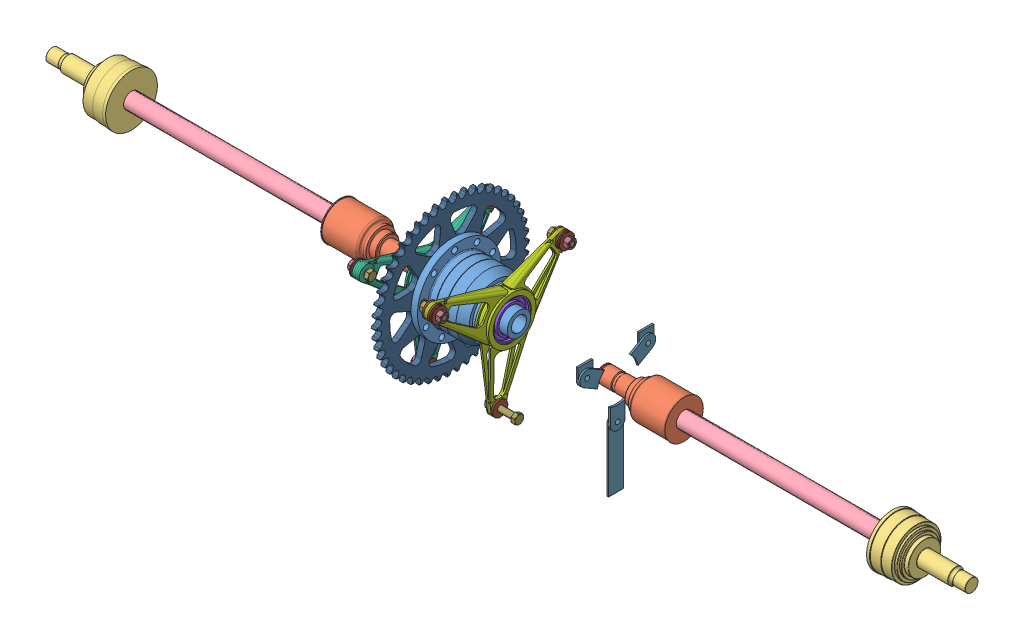
SolidWorks assembly AxleRear, configuration Simplified. Lengths in mm.
Overall size (1562.27 332.85 319.63).
54 component instances, 14 part files, 101 mates.
Components (placement in the parent):
- DifferentialHonda-1: DifferentialHonda [Default] at (-112.1 0 0) x (1 0 0) z (0 -0.982925 0.184005)
- HalfshaftCivicLeft-1: HalfshaftCivicLeft [Default] at (-315.2356 0 0) x (1 0 0) z (0 -0.94625 -0.323438) size (624.85 124.16 124.16) (flexible)
  - CVjointCivicInner-1: CVjointCivicInner [Default] at origin size (136.25 65.07 65.07)
  - CVjointCivicOuter-1: CVjointCivicOuter [Default] at (-354 0 0) x (-1 0 0) z (0 -0.656823 -0.754045) size (134.6 88 88)
  - AxleLeftRear-1: AxleLeftRear [Default] at (-177 0 0) x (1 0 0) z (0 -0.10869 0.994076) size (354 27 27)
- HalfshaftCivicLeft-3: HalfshaftCivicLeft [Default] at (269.8356 0 0) x (-1 0 0) z (0 -0.942827 -0.333282) size (624.85 124.16 124.16)
  - CVjointCivicInner-1: CVjointCivicInner [Default] at origin size (136.25 65.07 65.07)
  - CVjointCivicOuter-1: CVjointCivicOuter [Default] at (-354 0 0) x (-1 0 0) z (0 -0.656823 -0.754045) size (134.6 88 88)
  - AxleLeftRear-1: AxleLeftRear [Default] at (-177 0 0) x (1 0 0) z (0 -0.10869 0.994076) size (354 27 27)
- Basic Internal Retaining Ring_am-1: Basic Internal Retaining Ring_am [B27.7M - 3BM1-70] at (-39 0 0) x (0 0.02748 -0.999622) z (1 0 0)
- Basic Internal Retaining Ring_am-2: Basic Internal Retaining Ring_am [B27.7M - 3BM1-70] at (-144.05 0 0) x (0 0.383049 0.923728) z (1 0 0)
- DifferentialSupportLeft5-1: DifferentialSupportLeft5 [Finished Part] at (-127.45 0 0) x (0 0 1) z (-1 0 0)
- DifferentialSupportRight3-1: DifferentialSupportRight3 [Finished Part] at (-22.25 0 0) x (0 0 1) z (-1 0 0)
- Radial Ball Bearing_68_SKF-1: Radial Ball Bearing_68_SKF [SKF - 6008 - 16,SI,NC,16_68] at (-31.5 0 0)
- Radial Ball Bearing_68_SKF-2: Radial Ball Bearing_68_SKF [SKF - 6008 - 16,SI,NC,16_68] at (-136.55 0 0) x (-1 0 0) z (0 -0.924225 -0.381849)
- Hex Flange Machine Screw_AM-2: Hex Flange Machine Screw_AM [B18.6.7M - M10 x 1.5 x 20 Indented HFMS --20N] at (-143.1226 11.5003 61.4328)
- Sprocket50Real-1: Sprocket50Real [Default] at (-127.7363 0 0) x (0 0.982925 -0.184005) z (1 0 0)
- Flat Washer Type B Regular_AI-1: Flat Washer Type B Regular_AI [Regular FW 0.375] at (-168.05 62.2 116.6) x (1 0 0) z (0 -0.091606 0.995795)
- Hex Bolt_AI-1: Hex Bolt_AI [HBOLT 0.3750-24x1.125x1-N] at (-143.2428 62.2 116.6) x (-1 0 0) z (0 0.99306 0.117612)
- Flat Washer Type B Regular_AI-2: Flat Washer Type B Regular_AI [Regular FW 0.375] at (-162.05 62.4 -100.2)
- Flat Washer Type B Regular_AI-3: Flat Washer Type B Regular_AI [Regular FW 0.375] at (-163.6502 62.4 -100.2)
- Flat Washer Type B Regular_AI-4: Flat Washer Type B Regular_AI [Regular FW 0.375] at (-156.05 62.4 -100.2) x (-1 0 0) z (0 0.924225 0.381849)
- Flat Washer Type B Regular_AI-5: Flat Washer Type B Regular_AI [Regular FW 0.375] at (-154.4498 62.4 -100.2) x (-1 0 0) z (0 0.924225 0.381849)
- Flat Washer Type B Regular_AI-6: Flat Washer Type B Regular_AI [Regular FW 0.375] at (-43 62.4 -100.2)
- Flat Washer Type B Regular_AI-7: Flat Washer Type B Regular_AI [Regular FW 0.375] at (-44.6002 62.4 -100.2)
- Flat Washer Type B Regular_AI-8: Flat Washer Type B Regular_AI [Regular FW 0.375] at (-37 62.4 -100.2) x (-1 0 0) z (0 0.924225 0.381849)
- Flat Washer Type B Regular_AI-9: Flat Washer Type B Regular_AI [Regular FW 0.375] at (-35.3998 62.4 -100.2) x (-1 0 0) z (0 0.924225 0.381849)
- Flat Washer Type B Regular_AI-10: Flat Washer Type B Regular_AI [Regular FW 0.375] at (-43 62.2 116.6)
- Flat Washer Type B Regular_AI-11: Flat Washer Type B Regular_AI [Regular FW 0.375] at (-44.6002 62.2 116.6)
- Flat Washer Type B Regular_AI-12: Flat Washer Type B Regular_AI [Regular FW 0.375] at (-37 62.2 116.6) x (-1 0 0) z (0 0.924225 0.381849)
- Flat Washer Type B Regular_AI-13: Flat Washer Type B Regular_AI [Regular FW 0.375] at (-35.3998 62.2 116.6) x (-1 0 0) z (0 0.924225 0.381849)
- Flat Washer Type B Regular_AI-14: Flat Washer Type B Regular_AI [Regular FW 0.375] at (-162.05 -131.586 8.7)
- Flat Washer Type B Regular_AI-15: Flat Washer Type B Regular_AI [Regular FW 0.375] at (-163.6502 -131.586 8.7)
- Flat Washer Type B Regular_AI-16: Flat Washer Type B Regular_AI [Regular FW 0.375] at (-43 -131.586 8.7)
- Flat Washer Type B Regular_AI-19: Flat Washer Type B Regular_AI [Regular FW 0.375] at (-156.05 -131.586 8.7) x (-1 0 0) z (0 0.924225 0.381849)
- Flat Washer Type B Regular_AI-20: Flat Washer Type B Regular_AI [Regular FW 0.375] at (-154.4498 -131.586 8.7) x (-1 0 0) z (0 0.924225 0.381849)
- Flat Washer Type B Regular_AI-21: Flat Washer Type B Regular_AI [Regular FW 0.375] at (-37 -131.586 8.7) x (-1 0 0) z (0 0.924225 0.381849)
- Flat Washer Type B Regular_AI-22: Flat Washer Type B Regular_AI [Regular FW 0.375] at (-35.3998 -131.586 8.7) x (-1 0 0) z (0 0.924225 0.381849)
- Hex Nut_AI-4: Hex Nut_AI [HNUT 0.3750-24-D-N] at (-178.21 62.2 116.6) x (0 0 1) z (-1 0 0)
- Hex Bolt_AI-2: Hex Bolt_AI [HBOLT 0.3750-24x1.125x1-N] at (-56.0076 62.2 116.6)
- Hex Bolt_AI-3: Hex Bolt_AI [HBOLT 0.3750-24x1.125x1-N] at (-56.0076 62.4 -100.2)
- Hex Bolt_AI-4: Hex Bolt_AI [HBOLT 0.3750-24x1.125x1-N] at (-143.0424 62.4 -100.2) x (-1 0 0) z (0 0.924225 0.381849)
- Hex Bolt_AI-5: Hex Bolt_AI [HBOLT 0.3750-24x1.875x1-N] at (-1.5924 -131.586 8.7) x (-1 0 0) z (0 0.053695 -0.998557)
- Hex Bolt_AI-6: Hex Bolt_AI [HBOLT 0.3750-24x1.125x1-N] at (-143.0424 -131.586 8.7) x (-1 0 0) z (0 0.924225 0.381849)
- Flat Washer Type B Regular_AI-23: Flat Washer Type B Regular_AI [Regular FW 0.375] at (-168.2504 62.4 -100.2)
- Flat Washer Type B Regular_AI-24: Flat Washer Type B Regular_AI [Regular FW 0.375] at (-168.2504 -131.586 8.7)
- Flat Washer Type B Regular_AI-26: Flat Washer Type B Regular_AI [Regular FW 0.375] at (-30.7996 62.2 116.6) x (-1 0 0) z (0 0.924225 0.381849)
- Flat Washer Type B Regular_AI-27: Flat Washer Type B Regular_AI [Regular FW 0.375] at (-30.7996 62.4 -100.2) x (-1 0 0) z (0 0.924225 0.381849)
- Hex Nut_AI-5: Hex Nut_AI [HNUT 0.3750-24-D-N] at (-178.4104 62.4 -100.2) x (0 0 1) z (-1 0 0)
- Hex Nut_AI-6: Hex Nut_AI [HNUT 0.3750-24-D-N] at (-178.4104 -131.586 8.7) x (0 0 1) z (-1 0 0)
- Hex Nut_AI-7: Hex Nut_AI [HNUT 0.3750-24-D-N] at (-20.6396 62.2 116.6) x (0 0 -1) z (1 0 0)
- Hex Nut_AI-8: Hex Nut_AI [HNUT 0.3750-24-D-N] at (-20.6396 62.4 -100.2) x (0 0 -1) z (1 0 0)
- Hex Nut_AI-9: Hex Nut_AI [HNUT 0.3750-24-D-N] at (-53.16 -131.586 8.7) x (0 -0.907423 -0.420219) z (-1 0 0)
- AxleExtensionMountR-1: AxleExtensionMountR [Default] at (154 0 0) x (0 0 -1) z (1 0 0) size (128.92 216 6)
Mates (geometry in assembly coordinates):
- Distance1: distance = 78.7 mm: line of DifferentialHonda-1 through (-78.7 12.8016 68.3839) axis (0 -0.184005 -0.982925); plane of assembly through (0 0 0) normal (1 0 0)
- Concentric3644: concentric: cylinder of assembly; cylinder of assembly; cylinder of Basic Internal Retaining Ring_am-2 through (-146.45 0 0) axis (1 0 0) radius 37.2; cylinder of DifferentialSupportLeft5-1 through (-158.3481 0 0) axis (-1 0 0) radius 37.2
- Coincident375: coincident: plane of assembly; plane of assembly; plane of Basic Internal Retaining Ring_am-2 through (-144.05 0 0) normal (1 0 0); plane of DifferentialSupportLeft5-1 through (-144.05 37.2 0) normal (-1 0 0)
- Parallel1: parallel: plane of assembly through (0 0 0) normal (0 1 0); plane of DifferentialSupportRight3-1 through (-22.25 0 0) normal (0 1 0); plane of assembly
- Concentric3646: concentric: cylinder of assembly; cylinder of assembly; cylinder of Basic Internal Retaining Ring_am-1 through (-41.4 0 0) axis (1 0 0) radius 37.2; cylinder of DifferentialSupportRight3-1 through (-53.1481 0 0) axis (-1 0 0) radius 37.2
- Coincident379: coincident: plane of assembly; plane of assembly; plane of Basic Internal Retaining Ring_am-1 through (-41.4 0 0) normal (-1 0 0); plane of DifferentialSupportRight3-1 through (-41.4 35 0) normal (1 0 0)
- Parallel2: parallel: plane of assembly through (0 0 0) normal (0 1 0); plane of DifferentialSupportLeft5-1 through (-127.45 0 0) normal (0 1 0); plane of assembly
- Concentric367796: concentric: cylinder of assembly; cylinder of assembly; cylinder of DifferentialHonda-1 through (-190.9432 0 0) axis (-1 0 0) radius 20; cylinder of Radial Ball Bearing_68_SKF-1 through (-52.1375 0 0) axis (1 0 0) radius 20
- Concentric367797: concentric: cylinder of assembly; cylinder of assembly; cylinder of DifferentialHonda-1 through (-190.9432 0 0) axis (-1 0 0) radius 20; cylinder of Radial Ball Bearing_68_SKF-2 through (-115.9125 0 0) axis (-1 0 0) radius 20
- Distance27: distance = 4 mm: plane of assembly; plane of assembly; plane of Radial Ball Bearing_68_SKF-2 through (-129.05 9.2408 -22.3662) normal (1 0 0); plane of DifferentialHonda-1 through (-125.05 4.5725 24.4257) normal (-1 0 0)
- Concentric367798: concentric: cylinder of assembly; cylinder of assembly; cylinder of Radial Ball Bearing_68_SKF-2 through (-115.9125 0 0) axis (-1 0 0) radius 34; cylinder of DifferentialSupportLeft5-1 through (-158.3481 0 0) axis (-1 0 0) radius 35
- Coincident42628: coincident: plane of assembly; plane of assembly; plane of Basic Internal Retaining Ring_am-2 through (-144.05 0 0) normal (1 0 0); plane of Radial Ball Bearing_68_SKF-2 through (-144.05 12.601 -30.4994) normal (-1 0 0)
- Concentric367807: concentric: cylinder of assembly; cylinder of assembly; cylinder of Radial Ball Bearing_68_SKF-1 through (-52.1375 0 0) axis (1 0 0) radius 34; cylinder of DifferentialSupportRight3-1 through (-53.1481 0 0) axis (-1 0 0) radius 34
- Concentric367809: concentric: cylinder of assembly; cylinder of assembly; cylinder of DifferentialHonda-1 through (-190.9432 0 0) axis (-1 0 0) radius 71.2; cylinder of Sprocket50Real-1 through (-132.4226 0 0) axis (1 0 0) radius 52.5
- Coincident42637: coincident: plane of assembly; plane of assembly; plane of DifferentialHonda-1 through (-123.05 13.1011 69.9843) normal (-1 0 0); plane of Sprocket50Real-1 through (-123.05 30.5898 127.767) normal (1 0 0)
- Concentric367810: concentric: cylinder of assembly; cylinder of assembly; cylinder of DifferentialHonda-1 through (-97.9579 11.5003 61.4328) axis (-1 0 0) radius 5; cylinder of Sprocket50Real-1 through (-132.4226 11.5003 61.4328) axis (1 0 0) radius 5
- Concentric367811: concentric: cylinder of assembly; cylinder of assembly; cylinder of Hex Flange Machine Screw_AM-2 through (-168.5226 11.5003 61.4328) axis (-1 0 0) radius 5; cylinder of Sprocket50Real-1 through (-132.4226 11.5003 61.4328) axis (1 0 0) radius 5
- Coincident42638: coincident: plane of assembly; plane of assembly; plane of Hex Flange Machine Screw_AM-2 through (-132.4226 16.5003 61.4328) normal (1 0 0); plane of Sprocket50Real-1 through (-132.4226 30.5898 127.767) normal (-1 0 0)
- Concentric367812: concentric: cylinder of assembly; cylinder of assembly; cylinder of DifferentialSupportLeft5-1 through (-153.05 62.2 116.6) axis (1 0 0) radius 4.7625; cylinder of Hex Bolt_AI-1 through (-143.2428 62.2 116.6) axis (1 0 0) radius 4.7625
- Distance28: distance = 3 mm: plane of assembly; plane of assembly; plane of DifferentialSupportLeft5-1 through (-153.05 62.2 116.6) normal (1 0 0); plane of Hex Bolt_AI-1 through (-150.05 61.2307 124.7844) normal (-1 0 0)
- Coincident42640: coincident: plane of assembly; plane of assembly; plane of Basic Internal Retaining Ring_am-1 through (-39 0 0) normal (1 0 0); plane of Radial Ball Bearing_68_SKF-1 through (-39 29.8 0) normal (-1 0 0)
- Concentric367816: concentric: cylinder of assembly; cylinder of assembly; cylinder of Flat Washer Type B Regular_AI-1 through (-202.975 62.2 116.6) axis (-1 0 0) radius 5.1562; cylinder of Hex Bolt_AI-1 through (-143.2428 62.2 116.6) axis (1 0 0) radius 4.7625
- Distance30: distance = 3 mm: plane of assembly; plane of assembly; plane of Flat Washer Type B Regular_AI-1 through (-168.05 67.3345 117.0723) normal (1 0 0); plane of DifferentialSupportLeft5-1 through (-165.05 62.2 116.6) normal (-1 0 0)
- Distance29: distance = 0 mm: plane of assembly; plane of assembly; plane of Radial Ball Bearing_68_SKF-1 through (-39 24.2 0) normal (-1 0 0); plane of DifferentialHonda-1 through (-39 4.3701 23.3445) normal (1 0 0)
- Coincident42645: coincident: point of DifferentialSupportLeft5-1; plane of assembly
- Coincident42646: coincident: point of DifferentialSupportLeft5-1; plane of assembly
- Concentric367817: concentric: cylinder of assembly; cylinder of assembly; cylinder of DifferentialSupportLeft5-1 through (-159.05 62.4 -100.2) axis (-1 0 0) radius 4.7625; cylinder of Flat Washer Type B Regular_AI-2 through (-196.975 62.4 -100.2) axis (-1 0 0) radius 5.1562
- Coincident42647: coincident: plane of assembly; plane of assembly; plane of DifferentialSupportLeft5-1 through (-162.05 33.5278 -17.8853) normal (-1 0 0); plane of Flat Washer Type B Regular_AI-2 through (-162.05 67.5562 -100.2) normal (1 0 0)
- Concentric367818: concentric: cylinder of assembly; cylinder of assembly; cylinder of Flat Washer Type B Regular_AI-2 through (-196.975 62.4 -100.2) axis (-1 0 0) radius 5.1562; cylinder of Flat Washer Type B Regular_AI-3 through (-198.5752 62.4 -100.2) axis (-1 0 0) radius 5.1562
- Coincident42648: coincident: plane of assembly; plane of assembly; plane of Flat Washer Type B Regular_AI-2 through (-163.6502 75.1 -100.2) normal (-1 0 0); plane of Flat Washer Type B Regular_AI-3 through (-163.6502 67.5562 -100.2) normal (1 0 0)
- Concentric367819: concentric: cylinder of assembly; cylinder of assembly; cylinder of DifferentialSupportLeft5-1 through (-159.05 62.4 -100.2) axis (1 0 0) radius 4.7625; cylinder of Flat Washer Type B Regular_AI-4 through (-121.125 62.4 -100.2) axis (1 0 0) radius 5.1562
- Coincident42649: coincident: plane of assembly; plane of assembly; plane of DifferentialSupportLeft5-1 through (-156.05 34.4691 -132.9088) normal (1 0 0); plane of Flat Washer Type B Regular_AI-4 through (-156.05 60.4311 -95.4345) normal (-1 0 0)
- Concentric367820: concentric: cylinder of assembly; cylinder of assembly; cylinder of Flat Washer Type B Regular_AI-4 through (-121.125 62.4 -100.2) axis (1 0 0) radius 5.1562; cylinder of Flat Washer Type B Regular_AI-5 through (-119.5248 62.4 -100.2) axis (1 0 0) radius 5.1562
- Coincident42650: coincident: plane of assembly; plane of assembly; plane of Flat Washer Type B Regular_AI-4 through (-154.4498 57.5505 -88.4623) normal (1 0 0); plane of Flat Washer Type B Regular_AI-5 through (-154.4498 60.4311 -95.4345) normal (-1 0 0)
- Concentric367821: concentric: cylinder of assembly; cylinder of assembly; cylinder of DifferentialSupportRight3-1 through (-40 62.4 -100.2) axis (-1 0 0) radius 4.7625; cylinder of Flat Washer Type B Regular_AI-6 through (-77.925 62.4 -100.2) axis (-1 0 0) radius 5.1562
- Coincident42651: coincident: plane of assembly; plane of assembly; plane of DifferentialSupportRight3-1 through (-43 33.5278 -17.8853) normal (-1 0 0); plane of Flat Washer Type B Regular_AI-6 through (-43 67.5562 -100.2) normal (1 0 0)
- Concentric367822: concentric: cylinder of assembly; cylinder of assembly; cylinder of Flat Washer Type B Regular_AI-6 through (-77.925 62.4 -100.2) axis (-1 0 0) radius 5.1562; cylinder of Flat Washer Type B Regular_AI-7 through (-79.5252 62.4 -100.2) axis (-1 0 0) radius 5.1562
- Coincident42652: coincident: plane of assembly; plane of assembly; plane of Flat Washer Type B Regular_AI-6 through (-44.6002 75.1 -100.2) normal (-1 0 0); plane of Flat Washer Type B Regular_AI-7 through (-44.6002 67.5562 -100.2) normal (1 0 0)
- Concentric367823: concentric: cylinder of assembly; cylinder of assembly; cylinder of DifferentialSupportRight3-1 through (-40 62.4 -100.2) axis (1 0 0) radius 4.7625; cylinder of Flat Washer Type B Regular_AI-8 through (-2.075 62.4 -100.2) axis (1 0 0) radius 5.1562
- Coincident42653: coincident: plane of assembly; plane of assembly; plane of DifferentialSupportRight3-1 through (-37 34.4691 -132.9088) normal (1 0 0); plane of Flat Washer Type B Regular_AI-8 through (-37 60.4311 -95.4345) normal (-1 0 0)
- Concentric367824: concentric: cylinder of assembly; cylinder of assembly; cylinder of Flat Washer Type B Regular_AI-8 through (-2.075 62.4 -100.2) axis (1 0 0) radius 5.1562; cylinder of Flat Washer Type B Regular_AI-9 through (-0.4748 62.4 -100.2) axis (1 0 0) radius 5.1562
- Coincident42654: coincident: plane of assembly; plane of assembly; plane of Flat Washer Type B Regular_AI-8 through (-35.3998 57.5505 -88.4623) normal (1 0 0); plane of Flat Washer Type B Regular_AI-9 through (-35.3998 60.4311 -95.4345) normal (-1 0 0)
- Concentric367825: concentric: cylinder of assembly; cylinder of assembly; cylinder of DifferentialSupportRight3-1 through (-21 62.2 116.6) axis (-1 0 0) radius 4.7625; cylinder of Flat Washer Type B Regular_AI-10 through (-77.925 62.2 116.6) axis (-1 0 0) radius 5.1562
- Coincident42655: coincident: plane of assembly; plane of assembly; plane of DifferentialSupportRight3-1 through (-43 33.5278 -17.8853) normal (-1 0 0); plane of Flat Washer Type B Regular_AI-10 through (-43 67.3562 116.6) normal (1 0 0)
- Concentric367826: concentric: cylinder of assembly; cylinder of assembly; cylinder of Flat Washer Type B Regular_AI-10 through (-77.925 62.2 116.6) axis (-1 0 0) radius 5.1562; cylinder of Flat Washer Type B Regular_AI-11 through (-79.5252 62.2 116.6) axis (-1 0 0) radius 5.1562
- Coincident42656: coincident: plane of assembly; plane of assembly; plane of Flat Washer Type B Regular_AI-10 through (-44.6002 74.9 116.6) normal (-1 0 0); plane of Flat Washer Type B Regular_AI-11 through (-44.6002 67.3562 116.6) normal (1 0 0)
- Concentric367827: concentric: cylinder of assembly; cylinder of assembly; cylinder of DifferentialSupportRight3-1 through (-40 62.2 116.6) axis (-1 0 0) radius 4.7625; cylinder of Flat Washer Type B Regular_AI-12 through (-2.075 62.2 116.6) axis (1 0 0) radius 5.1562
- Coincident42657: coincident: plane of assembly; plane of assembly; plane of DifferentialSupportRight3-1 through (-37 106.548 118.9981) normal (1 0 0); plane of Flat Washer Type B Regular_AI-12 through (-37 60.2311 121.3655) normal (-1 0 0)
- Concentric367828: concentric: cylinder of assembly; cylinder of assembly; cylinder of Flat Washer Type B Regular_AI-12 through (-2.075 62.2 116.6) axis (1 0 0) radius 5.1562; cylinder of Flat Washer Type B Regular_AI-13 through (-0.4748 62.2 116.6) axis (1 0 0) radius 5.1562
- Coincident42658: coincident: plane of assembly; plane of assembly; plane of Flat Washer Type B Regular_AI-12 through (-35.3998 57.3505 128.3377) normal (1 0 0); plane of Flat Washer Type B Regular_AI-13 through (-35.3998 60.2311 121.3655) normal (-1 0 0)
- Concentric367829: concentric: cylinder of assembly; cylinder of assembly; cylinder of DifferentialSupportLeft5-1 through (-124.05 -131.586 8.7) axis (-1 0 0) radius 4.7625; cylinder of Flat Washer Type B Regular_AI-14 through (-196.975 -131.586 8.7) axis (-1 0 0) radius 5.1562
- Coincident42659: coincident: plane of assembly; plane of assembly; plane of DifferentialSupportLeft5-1 through (-162.05 33.5278 -17.8853) normal (-1 0 0); plane of Flat Washer Type B Regular_AI-14 through (-162.05 -126.4298 8.7) normal (1 0 0)
- Concentric367830: concentric: cylinder of assembly; cylinder of assembly; cylinder of Flat Washer Type B Regular_AI-14 through (-196.975 -131.586 8.7) axis (-1 0 0) radius 5.1562; cylinder of Flat Washer Type B Regular_AI-15 through (-198.5752 -131.586 8.7) axis (-1 0 0) radius 5.1562
- Coincident42660: coincident: plane of assembly; plane of assembly; plane of Flat Washer Type B Regular_AI-14 through (-163.6502 -118.886 8.7) normal (-1 0 0); plane of Flat Washer Type B Regular_AI-15 through (-163.6502 -126.4298 8.7) normal (1 0 0)
- Concentric367831: concentric: cylinder of assembly; cylinder of assembly; cylinder of DifferentialSupportRight3-1 through (-5 -131.586 8.7) axis (-1 0 0) radius 4.7625; cylinder of Flat Washer Type B Regular_AI-16 through (-77.925 -131.586 8.7) axis (-1 0 0) radius 5.1562
- Coincident42661: coincident: plane of assembly; plane of assembly; plane of DifferentialSupportRight3-1 through (-43 33.5278 -17.8853) normal (-1 0 0); plane of Flat Washer Type B Regular_AI-16 through (-43 -126.4298 8.7) normal (1 0 0)
- Concentric367834: concentric: cylinder of assembly; cylinder of assembly; cylinder of Flat Washer Type B Regular_AI-19 through (-121.125 -131.586 8.7) axis (1 0 0) radius 5.1562; cylinder of DifferentialSupportLeft5-1 through (-156.05 -131.586 8.7) axis (1 0 0) radius 4.7625
- Coincident42664: coincident: plane of assembly; plane of assembly; plane of DifferentialSupportLeft5-1 through (-156.05 -118.438 -38) normal (1 0 0); plane of Flat Washer Type B Regular_AI-19 through (-156.05 -133.5549 13.4655) normal (-1 0 0)
- Concentric367835: concentric: cylinder of assembly; cylinder of assembly; cylinder of Flat Washer Type B Regular_AI-19 through (-121.125 -131.586 8.7) axis (1 0 0) radius 5.1562; cylinder of Flat Washer Type B Regular_AI-20 through (-119.5248 -131.586 8.7) axis (1 0 0) radius 5.1562
- Coincident42665: coincident: plane of assembly; plane of assembly; plane of Flat Washer Type B Regular_AI-19 through (-154.4498 -136.4355 20.4377) normal (1 0 0); plane of Flat Washer Type B Regular_AI-20 through (-154.4498 -133.5549 13.4655) normal (-1 0 0)
- Concentric367836: concentric: cylinder of assembly; cylinder of assembly; cylinder of DifferentialSupportRight3-1 through (-37 -131.586 8.7) axis (1 0 0) radius 4.7625; cylinder of Flat Washer Type B Regular_AI-21 through (-2.075 -131.586 8.7) axis (1 0 0) radius 5.1562
- Coincident42666: coincident: plane of assembly; plane of assembly; plane of DifferentialSupportRight3-1 through (-37 -118.438 -38) normal (1 0 0); plane of Flat Washer Type B Regular_AI-21 through (-37 -133.5549 13.4655) normal (-1 0 0)
- Concentric367837: concentric: cylinder of assembly; cylinder of assembly; cylinder of Flat Washer Type B Regular_AI-21 through (-2.075 -131.586 8.7) axis (1 0 0) radius 5.1562; cylinder of Flat Washer Type B Regular_AI-22 through (-0.4748 -131.586 8.7) axis (1 0 0) radius 5.1562
- Coincident42667: coincident: plane of assembly; plane of assembly; plane of Flat Washer Type B Regular_AI-21 through (-35.3998 -136.4355 20.4377) normal (1 0 0); plane of Flat Washer Type B Regular_AI-22 through (-35.3998 -133.5549 13.4655) normal (-1 0 0)
- Concentric367838: concentric: cylinder of assembly; cylinder of assembly; cylinder of Hex Bolt_AI-1 through (-143.2428 62.2 116.6) axis (1 0 0) radius 4.7625; cylinder of Hex Nut_AI-4 through (-153.1725 62.2 116.6) axis (-1 0 0) radius 4.7625
- Coincident42668: coincident: plane of assembly; plane of assembly; plane of Flat Washer Type B Regular_AI-1 through (-169.6502 74.8466 117.7634) normal (-1 0 0); plane of Hex Nut_AI-4 through (-169.6502 62.2 102.3252) normal (1 0 0)
- Concentric367839: concentric: cylinder of assembly; cylinder of assembly; cylinder of Flat Washer Type B Regular_AI-11 through (-79.5252 62.2 116.6) axis (-1 0 0) radius 5.1562; cylinder of Hex Bolt_AI-2 through (-56.0076 62.2 116.6) axis (-1 0 0) radius 4.7625
- Distance33: distance = 3 mm: plane of assembly; plane of assembly; plane of Flat Washer Type B Regular_AI-11 through (-46.2004 74.9 116.6) normal (-1 0 0); plane of Hex Bolt_AI-2 through (-49.2004 70.4416 116.6) normal (1 0 0)
- Concentric367840: concentric: cylinder of assembly; cylinder of assembly; cylinder of Flat Washer Type B Regular_AI-7 through (-79.5252 62.4 -100.2) axis (-1 0 0) radius 5.1562; cylinder of Hex Bolt_AI-3 through (-56.0076 62.4 -100.2) axis (-1 0 0) radius 4.7625
- Distance32: distance = 3 mm: plane of assembly; plane of assembly; plane of Flat Washer Type B Regular_AI-7 through (-46.2004 75.1 -100.2) normal (-1 0 0); plane of Hex Bolt_AI-3 through (-49.2004 70.6416 -100.2) normal (1 0 0)
- Concentric367841: concentric: cylinder of assembly; cylinder of assembly; cylinder of Flat Washer Type B Regular_AI-5 through (-119.5248 62.4 -100.2) axis (1 0 0) radius 5.1562; cylinder of Hex Bolt_AI-4 through (-143.0424 62.4 -100.2) axis (1 0 0) radius 4.7625
- Distance31: distance = 3 mm: plane of assembly; plane of assembly; plane of Flat Washer Type B Regular_AI-5 through (-152.8496 57.5505 -88.4623) normal (1 0 0); plane of Hex Bolt_AI-4 through (-149.8496 59.253 -92.5829) normal (-1 0 0)
- Concentric367842: concentric: cylinder of assembly; cylinder of assembly; cylinder of DifferentialSupportRight3-1 through (-5 -131.586 8.7) axis (-1 0 0) radius 4.7625; cylinder of Hex Bolt_AI-5 through (-1.5924 -131.586 8.7) axis (1 0 0) radius 4.7625
- Concentric367843: concentric: cylinder of assembly; cylinder of assembly; cylinder of Flat Washer Type B Regular_AI-20 through (-119.5248 -131.586 8.7) axis (1 0 0) radius 5.1562; cylinder of Hex Bolt_AI-6 through (-143.0424 -131.586 8.7) axis (1 0 0) radius 4.7625
- Distance34: distance = 3 mm: plane of assembly; plane of assembly; plane of Flat Washer Type B Regular_AI-20 through (-152.8496 -136.4355 20.4377) normal (1 0 0); plane of Hex Bolt_AI-6 through (-149.8496 -134.733 16.3171) normal (-1 0 0)
- Concentric367844: concentric: cylinder of assembly; cylinder of assembly; cylinder of Flat Washer Type B Regular_AI-3 through (-198.5752 62.4 -100.2) axis (-1 0 0) radius 5.1562; cylinder of Flat Washer Type B Regular_AI-23 through (-203.1754 62.4 -100.2) axis (-1 0 0) radius 5.1562
- Distance36: distance = 3 mm: plane of assembly; plane of assembly; plane of Flat Washer Type B Regular_AI-3 through (-165.2504 75.1 -100.2) normal (-1 0 0); plane of Flat Washer Type B Regular_AI-23 through (-168.2504 67.5562 -100.2) normal (1 0 0)
- Concentric367845: concentric: cylinder of assembly; cylinder of assembly; cylinder of Flat Washer Type B Regular_AI-15 through (-198.5752 -131.586 8.7) axis (-1 0 0) radius 5.1562; cylinder of Flat Washer Type B Regular_AI-24 through (-203.1754 -131.586 8.7) axis (-1 0 0) radius 5.1562
- Distance37: distance = 3 mm: plane of assembly; plane of assembly; plane of Flat Washer Type B Regular_AI-15 through (-165.2504 -118.886 8.7) normal (-1 0 0); plane of Flat Washer Type B Regular_AI-24 through (-168.2504 -126.4298 8.7) normal (1 0 0)
- Concentric367847: concentric: cylinder of assembly; cylinder of assembly; cylinder of Flat Washer Type B Regular_AI-13 through (-0.4748 62.2 116.6) axis (1 0 0) radius 5.1562; cylinder of Flat Washer Type B Regular_AI-26 through (4.1254 62.2 116.6) axis (1 0 0) radius 5.1562
- Distance39: distance = 3 mm: plane of assembly; plane of assembly; plane of Flat Washer Type B Regular_AI-13 through (-33.7996 57.3505 128.3377) normal (1 0 0); plane of Flat Washer Type B Regular_AI-26 through (-30.7996 60.2311 121.3655) normal (-1 0 0)
- Concentric367848: concentric: cylinder of assembly; cylinder of assembly; cylinder of Flat Washer Type B Regular_AI-9 through (-0.4748 62.4 -100.2) axis (1 0 0) radius 5.1562; cylinder of Flat Washer Type B Regular_AI-27 through (4.1254 62.4 -100.2) axis (1 0 0) radius 5.1562
- Distance40: distance = 3 mm: plane of assembly; plane of assembly; plane of Flat Washer Type B Regular_AI-9 through (-33.7996 57.5505 -88.4623) normal (1 0 0); plane of Flat Washer Type B Regular_AI-27 through (-30.7996 60.4311 -95.4345) normal (-1 0 0)
- Concentric367849: concentric: cylinder of assembly; cylinder of assembly; cylinder of Flat Washer Type B Regular_AI-23 through (-203.1754 62.4 -100.2) axis (-1 0 0) radius 5.1562; cylinder of Hex Nut_AI-5 through (-153.3729 62.4 -100.2) axis (-1 0 0) radius 4.7625
- Coincident42679: coincident: plane of assembly; plane of assembly; plane of Flat Washer Type B Regular_AI-23 through (-169.8506 75.1 -100.2) normal (-1 0 0); plane of Hex Nut_AI-5 through (-169.8506 62.4 -114.4748) normal (1 0 0)
- Concentric367850: concentric: cylinder of assembly; cylinder of assembly; cylinder of Flat Washer Type B Regular_AI-24 through (-203.1754 -131.586 8.7) axis (-1 0 0) radius 5.1562; cylinder of Hex Nut_AI-6 through (-153.3729 -131.586 8.7) axis (-1 0 0) radius 4.7625
- Coincident42680: coincident: plane of assembly; plane of assembly; plane of Flat Washer Type B Regular_AI-24 through (-169.8506 -118.886 8.7) normal (-1 0 0); plane of Hex Nut_AI-6 through (-169.8506 -131.586 -5.5748) normal (1 0 0)
- Concentric367851: concentric: cylinder of assembly; cylinder of assembly; cylinder of Flat Washer Type B Regular_AI-26 through (4.1254 62.2 116.6) axis (1 0 0) radius 5.1562; cylinder of Hex Nut_AI-7 through (-45.6771 62.2 116.6) axis (1 0 0) radius 4.7625
- Coincident42681: coincident: plane of assembly; plane of assembly; plane of Flat Washer Type B Regular_AI-26 through (-29.1994 57.3505 128.3377) normal (1 0 0); plane of Hex Nut_AI-7 through (-29.1994 62.2 130.8748) normal (-1 0 0)
- Concentric367852: concentric: cylinder of assembly; cylinder of assembly; cylinder of Flat Washer Type B Regular_AI-27 through (4.1254 62.4 -100.2) axis (1 0 0) radius 5.1562; cylinder of Hex Nut_AI-8 through (-45.6771 62.4 -100.2) axis (1 0 0) radius 4.7625
- Coincident42682: coincident: plane of assembly; plane of assembly; plane of Flat Washer Type B Regular_AI-27 through (-29.1994 57.5505 -88.4623) normal (1 0 0); plane of Hex Nut_AI-8 through (-29.1994 62.4 -85.9252) normal (-1 0 0)
- Concentric367853: concentric: cylinder of assembly; cylinder of assembly; cylinder of Hex Bolt_AI-5 through (-1.5924 -131.586 8.7) axis (1 0 0) radius 4.7625; cylinder of Hex Nut_AI-9 through (-28.1225 -131.586 8.7) axis (-1 0 0) radius 4.7625
- Coincident42683: coincident: plane of assembly; plane of assembly; plane of Flat Washer Type B Regular_AI-16 through (-44.6002 -118.886 8.7) normal (-1 0 0); plane of Hex Nut_AI-9 through (-44.6002 -118.6327 14.6985) normal (1 0 0)
- Distance41: distance = 25.4 mm: plane of assembly; plane of assembly; plane of Hex Bolt_AI-5 through (-8.3996 -123.3563 9.1425) normal (-1 0 0); plane of Flat Washer Type B Regular_AI-22 through (-33.7996 -136.4355 20.4377) normal (1 0 0)
- Concentric367854: concentric: cylinder of DifferentialHonda-1 through (-190.9432 0 0) axis (-1 0 0) radius 12.9; cylinder of HalfshaftCivicLeft-1/CVjointCivicInner-1 through (-324.575 0 0) axis (-1 0 0) radius 13.97
- Distance42: distance = 87 mm: plane of HalfshaftCivicLeft-1/CVjointCivicInner-1 through (-233.6 -6.4696 18.9274) normal (1 0 0); plane of DifferentialHonda-1 through (-146.6 3.6801 19.6585) normal (-1 0 0)
- Concentric367855: concentric: cylinder of HalfshaftCivicLeft-3/CVjointCivicInner-1 through (279.175 0 0) axis (1 0 0) radius 13.97; cylinder of DifferentialHonda-1 through (-190.9432 0 0) axis (-1 0 0) radius 12.9
- Distance43: distance = 199 mm: plane of DifferentialHonda-1 through (-10.8 3.6801 19.6585) normal (1 0 0); plane of HalfshaftCivicLeft-3/CVjointCivicInner-1 through (188.2 6.6665 -18.8589) normal (-1 0 0)
- Coincident42686: coincident: plane of assembly through (0 0 0) normal (0 1 0); plane of AxleExtensionMountR-1 through (154 0 0) normal (0 1 0); plane of assembly
- Coincident42687: coincident: plane of assembly through (0 0 0) normal (0 0 1); plane of AxleExtensionMountR-1 through (154 0 0) normal (0 0 -1); plane of assembly
- Distance44: distance = 154 mm: plane of assembly through (0 0 0) normal (1 0 0); plane of AxleExtensionMountR-1 through (154 0 0) normal (1 0 0); plane of assembly
